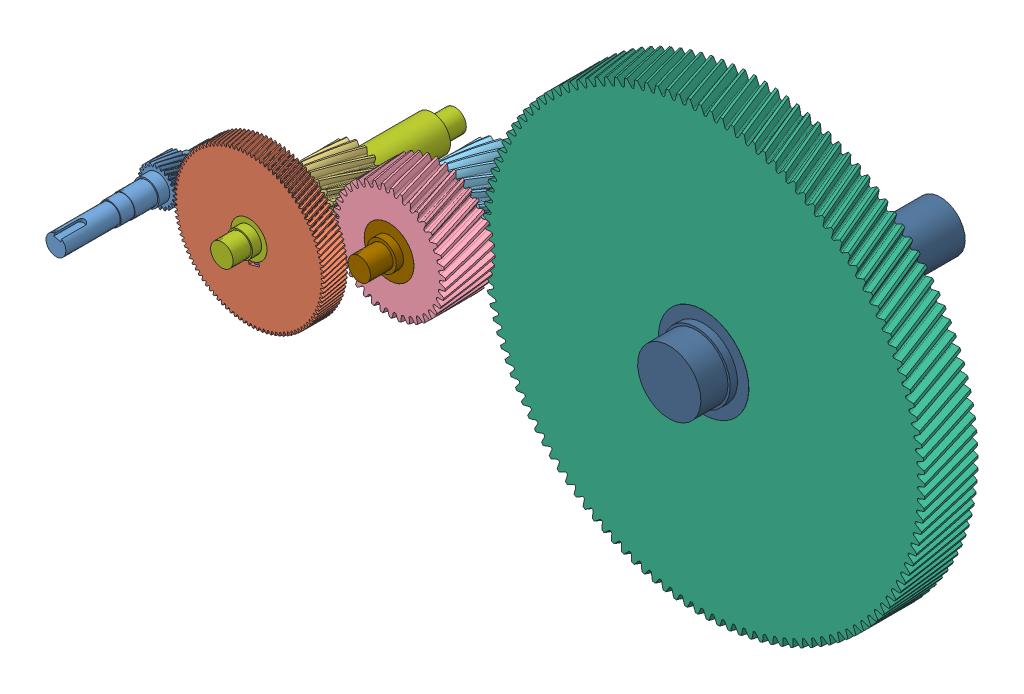
SolidWorks assembly Reductor de 3 Etapas, configuration Predeterminado. Lengths in mm.
Overall size (837.24 683.47 507.91).
12 component instances, 11 part files, 38 mates.
Components (placement in the parent):
- Carcaza-1: Carcaza [Predeterminado] x (1 0 0) z (0 1 0) size (470.5 137.7 0)
- Engranaje Z1-1: Engranaje Z1 [Predeterminado] x (0.231141 0.97292 0) z (0 0 1) size (41.54 41.54 176)
- Engranaje Z2-1: Engranaje Z2 [Predeterminado] at (101 0 0) x (-0.966153 -0.25797 0) z (0 0 1) size (166.4 166.4 26.01)
- Engranaje Z3-1: Engranaje Z3 [Predeterminado] at (101 0 -80) x (-0.966153 -0.25797 0) z (0 0 1) size (66.25 66.25 57.01)
- Engranaje Z4-1: Engranaje Z4 [Predeterminado] at (190.5 0 -80) x (-0.861013 0.508583 0) z (0 0 1) size (124.85 124.84 55.01)
- Engranaje Z5-1: Engranaje Z5 [Predeterminado] at (190.5 0 -150) x (-0.861013 0.508583 0) z (0 0 1) size (84.47 84.47 60.96)
- Engranaje Z6-1: Engranaje Z6 [Predeterminado] at (470.5 0 -150) x (0.808576 -0.588391 0) z (0 0 1) size (489.25 489.25 58.84)
- Arbol 2° Etapa-1: Arbol 2° Etapa [Predeterminado] at (101 0 43) x (0.966153 0.25797 0) z (0 0 -1) size (45 45 258)
- Chaveta 12x8-1: Chaveta 12x8 [12x8x22] at (104.8953 -14.5889 -5) x (0 0 1) z (0.966153 0.25797 0) size (22 8 12)
- Chaveta 12x8-2: Chaveta 12x8 [12x8x49] at (105.1533 -15.5551 -98) x (0 0 1) z (0.966153 0.25797 0) size (49 8 12)
- Arbol 3° Etapa-1: Arbol 3° Etapa [Predeterminado] at (190.8382 -0.1998 -19.551) x (-0.508583 -0.861013 0) z (0 0 -1) size (60 60 226)
- Arbol Salida-1: Arbol Salida [Predeterminado] at (470.5 0 -156.465) x (0.808576 -0.588391 0) z (0 0 -1) size (110 110 300)
Mates (geometry in assembly coordinates):
- EnPosición1: in place: plane of Carcaza-1 through (0 0 0) normal (0 1 0); moOrthogonalPlaneRef_w of Carcaza-1 through (0 0 0) normal (0 0 -1); plane of Carcaza-1 through (0 0 0) normal (1 0 0); unknown of Carcaza-1
- Coincidente1: coincident aligned: plane of Carcaza-1; plane of assembly
- Coincidente2: coincident aligned: plane of Carcaza-1 through (0 0 0) normal (0 0 -1); moOrthogonalPlaneRef_w of assembly
- Coincidente3: coincident anti-aligned: plane of Carcaza-1 through (0 0 0) normal (1 0 0); moOrthogonalPlaneRef_w of assembly
- Coincidente5: coincident anti-aligned: line of Carcaza-1 through (0 0 0) axis (0 0 -1); line of Engranaje Z1-1 through (0 0 -13.05) axis (0 0 1)
- Coincidente6: coincident anti-aligned: line of Carcaza-1 through (0 0 0) axis (0 0 -1); line of Engranaje Z1-1 through (0 0 -13.05) axis (0 0 1)
- Coincidente7: coincident anti-aligned: plane of Carcaza-1 through (0 0 0) normal (0 0 -1); plane of Engranaje Z1-1 through (0 0 0) normal (0 0 1)
- Coincidente8: coincident anti-aligned: line of Carcaza-1 through (101 0 0) axis (0 0 -1); line of Engranaje Z2-1 through (101 0 -12.6125) axis (0 0 1)
- Coincidente9: coincident anti-aligned: plane of Carcaza-1 through (0 0 0) normal (0 0 -1); plane of Engranaje Z2-1 through (101 0 0) normal (0 0 1)
- Relación de posición de engranaje1: gear = 104 : 24 mm: cylinder of Engranaje Z1-1 through (0 0 13.5) axis (0 0 -1) radius 20.7343; cylinder of Engranaje Z2-1 through (101 0 13) axis (0 0 -1) radius 83.1611
- Coincidente10: coincident anti-aligned: line of Carcaza-1 through (101 0 0) axis (0 0 -1); line of Engranaje Z3-1 through (101 0 -108.387) axis (0 0 1)
- Coincidente11: coincident anti-aligned: plane of Carcaza-1 through (0 0 -80) normal (0 0 -1); plane of Engranaje Z3-1 through (101 0 -80) normal (0 0 1)
- Coincidente12: coincident anti-aligned: line of Carcaza-1 through (190.5 0 0) axis (0 0 -1); line of Engranaje Z4-1 through (190.5 0 -107.4495) axis (0 0 1)
- Coincidente13: coincident anti-aligned: plane of Carcaza-1 through (0 0 -80) normal (0 0 -1); plane of Engranaje Z4-1 through (190.5 0 -80) normal (0 0 1)
- Relación de posición de engranaje2: gear = 39 : 19 mm: cylinder of Engranaje Z3-1 through (101 0 -51.5) axis (0 0 -1) radius 33.0891; cylinder of Engranaje Z4-1 through (190.5 0 -52.5) axis (0 0 -1) radius 62.3804
- Coincidente14: coincident anti-aligned: plane of Engranaje Z2-1; plane of Engranaje Z3-1
- Coincidente15: coincident anti-aligned: line of Carcaza-1 through (190.5 0 0) axis (0 0 -1); line of Engranaje Z5-1 through (190.5 0 -180.4765) axis (0 0 1)
- Coincidente16: coincident anti-aligned: plane of Carcaza-1 through (0 0 -150) normal (0 0 -1); plane of Engranaje Z5-1 through (190.5 0 -150) normal (0 0 1)
- Coincidente17: coincident anti-aligned: line of Carcaza-1 through (470.5 0 0) axis (0 0 -1); line of Engranaje Z6-1 through (470.5 0 -179.414) axis (0 0 1)
- Coincidente18: coincident anti-aligned: plane of Carcaza-1 through (0 0 -150) normal (0 0 -1); plane of Engranaje Z6-1 through (470.5 0 -150) normal (0 0 1)
- Relación de posición de engranaje3: gear = 128 : 20 mm: cylinder of Engranaje Z5-1 through (190.5 0 -119.5235) axis (0 0 -1) radius 42.1849; cylinder of Engranaje Z6-1 through (470.5 0 -120.586) axis (0 0 -1) radius 244.5694
- Coincidente19: coincident aligned: plane of Engranaje Z4-1 through (190.5 0 -80) normal (-0.861013 0.508583 0); plane of Engranaje Z5-1 through (190.5 0 -150) normal (-0.861013 0.508583 0)
- Concéntrica1: concentric aligned: cylinder of Engranaje Z2-1 through (101 0 -13.0061) axis (0 0 1) radius 20; cylinder of Arbol 2° Etapa-1 through (101 0 43) axis (0 0 1) radius 21
- Coincidente20: coincident anti-aligned: plane of Engranaje Z2-1 through (101 0 -13) normal (0 0 -1); plane of Arbol 2° Etapa-1 through (95.8406 19.3231 -13) normal (0 0 1)
- Coincidente21: coincident aligned: plane of Engranaje Z2-1 through (112.7818 -20.8669 -13.0061) normal (-0.966153 -0.25797 0); plane of Arbol 2° Etapa-1 through (110.6923 -13.0411 5) normal (-0.966153 -0.25797 0)
- Coincidente22: coincident aligned: plane of Engranaje Z3-1 through (101.5749 -25.4118 -51.494) normal (0.966153 0.25797 0); plane of Arbol 2° Etapa-1 through (99.3564 -17.1029 -61) normal (0.966153 0.25797 0)
- Coincidente23: coincident anti-aligned: plane of Arbol 2° Etapa-1 through (104.8953 -14.5889 5) normal (0.25797 -0.966153 0); plane of Chaveta 12x8-1 through (104.8953 -14.5889 -5) normal (-0.25797 0.966153 0)
- Concéntrica2: concentric anti-aligned: cylinder of Arbol 2° Etapa-1 through (104.8953 -14.5889 -5) axis (0.25797 -0.966153 0) radius 6; cylinder of Chaveta 12x8-1 through (106.9591 -22.3181 -5) axis (-0.25797 0.966153 0) radius 6
- Concéntrica3: concentric anti-aligned: cylinder of Arbol 2° Etapa-1 through (104.8953 -14.5889 5) axis (0.25797 -0.966153 0) radius 6; cylinder of Chaveta 12x8-1 through (106.9591 -22.3181 5) axis (-0.25797 0.966153 0) radius 6
- Coincidente24: coincident anti-aligned: plane of Arbol 2° Etapa-1 through (105.1533 -15.5551 -61) normal (0.25797 -0.966153 0); plane of Chaveta 12x8-2 through (105.1533 -15.5551 -98) normal (-0.25797 0.966153 0)
- Concéntrica4: concentric anti-aligned: cylinder of Arbol 2° Etapa-1 through (105.1533 -15.5551 -61) axis (0.25797 -0.966153 0) radius 6; cylinder of Chaveta 12x8-2 through (107.2171 -23.2843 -61) axis (-0.25797 0.966153 0) radius 6
- Concéntrica5: concentric anti-aligned: cylinder of Arbol 2° Etapa-1 through (105.1533 -15.5551 -98) axis (0.25797 -0.966153 0) radius 6; cylinder of Chaveta 12x8-2 through (107.2171 -23.2843 -98) axis (-0.25797 0.966153 0) radius 6
- Concéntrica6: concentric anti-aligned: cylinder of Engranaje Z4-1 through (190.5 0 -107.5061) axis (0 0 1) radius 27.5; cylinder of Arbol 3° Etapa-1 through (190.5 0 -19.5) axis (0 0 -1) radius 27.5
- Coincidente26: coincident anti-aligned: plane of Engranaje Z4-1 through (190.5 0 -107.5) normal (0 0 -1); plane of Arbol 3° Etapa-1 through (214.1779 -13.986 -107.5) normal (0 0 1)
- Coincidente27: coincident aligned: plane of Engranaje Z4-1 through (190.5 0 -80) normal (-0.508583 -0.861013 0); plane of Arbol 3° Etapa-1 through (190.8382 -0.1998 -19.551) normal (-0.508583 -0.861013 0)
- Concéntrica7: concentric aligned: cylinder of Engranaje Z6-1 through (470.5 0 -179.42) axis (0 0 1) radius 50; cylinder of Arbol Salida-1 through (470.5 0 -82.414) axis (0 0 1) radius 50
- Coincidente28: coincident anti-aligned: plane of Engranaje Z6-1 through (470.5 0 -179.414) normal (0 0 -1); plane of Arbol Salida-1 through (499.9196 40.4288 -179.414) normal (0 0 1)
- Coincidente29: coincident aligned: plane of Engranaje Z6-1 through (470.5 0 -150) normal (0.808576 -0.588391 0); plane of Arbol Salida-1 through (470.5 0 -156.465) normal (0.808576 -0.588391 0)
